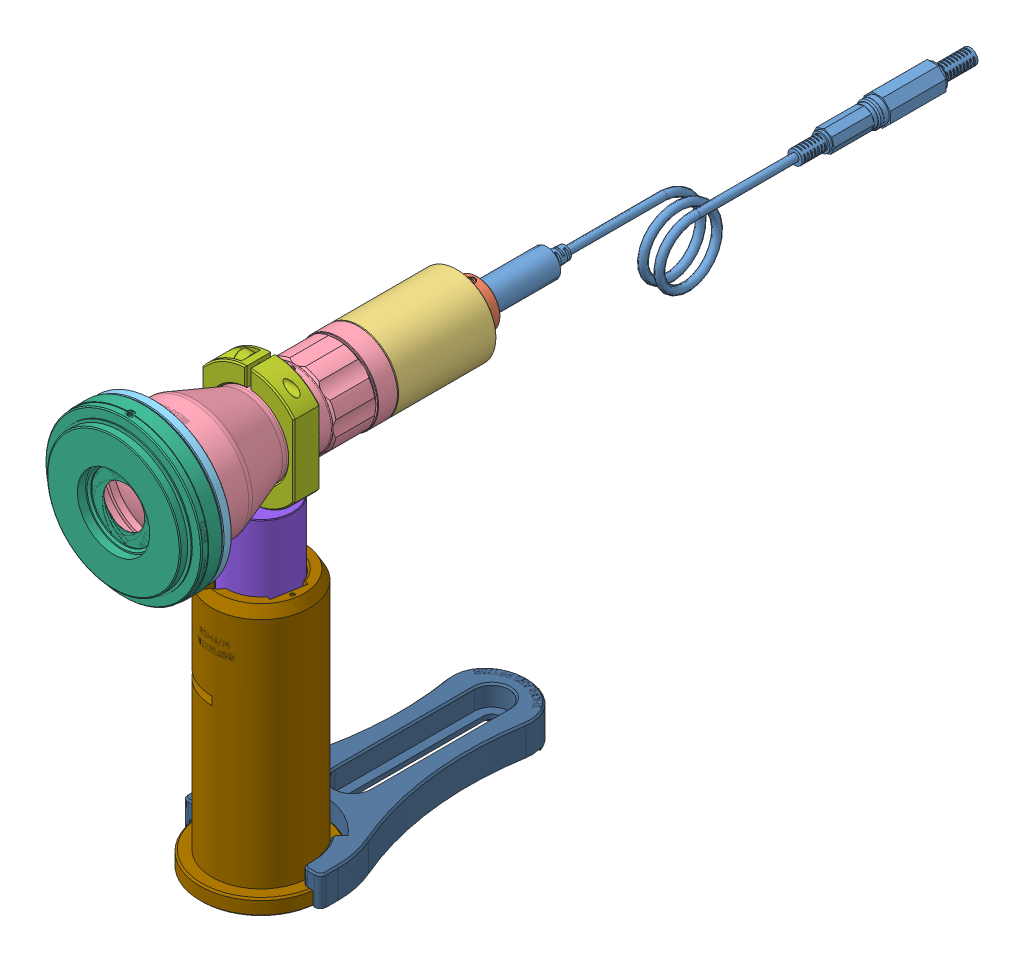
SolidWorks assembly alignment_laser_v1.0, configuration Default. Lengths in mm.
Overall size (60.96 177.6 318.27).
10 component instances, 10 part files, 28 mates.
Components (placement in the parent):
- CPS532-Solidworks-1: CPS532-Solidworks [Default] at origin size (23.32 32.38 223.65)
- AD11F-Solidworks-1: AD11F-Solidworks [Default] at (0 0 -2.981) x (-1 0 0) z (0 1 0) size (26.29 14.99 26.29)
- SM1M15-Solidworks-1: SM1M15-Solidworks [Default] at (1.3605 -23.9688 -18.2398) size (30.48 30.48 38.1)
- BE05-532-Solidworks-1: BE05-532-Solidworks [Default] at (0 0 34.5) size (45 45 85.5)
- SM2A30-Solidworks-1: SM2A30-Solidworks [Default] at (0 0 114.5) x (-1 0 0) z (0 0 -1) size (60.2 60.2 6.35)
- SM2D25D-Solidworks-1: SM2D25D-Solidworks [Default] at (6.3593 1.1475 119.8262) size (60.96 60.96 12.32)
- SM1RC_M-Solidworks-1: SM1RC_M-Solidworks [Web Drawing] at (0 0 78.26) x (-1 0 0) z (0 0 -1) size (35.56 44.69 10.16)
- RS100_M-Solidworks-1: RS100_M-Solidworks [Default] at (2.2631 -70.4202 70.8458) size (25 100 25.2)
- RSH4_M-Solidworks-1: RSH4_M-Solidworks [Default] at (36.1376 -109.0482 157.2021) x (0 0 1) z (-1 0 0) size (46.99 100.24 46.99)
- PF175B-Solidworks-1: PF175B-Solidworks [Default] at (0 -146.336 73.18) x (-1 0 0) z (0 0 -1) size (53.49 12.22 106.54)
Mates (geometry in assembly coordinates):
- Coincident1: coordinate: point of CPS532-Solidworks-1; point of assembly
- Concentric1: concentric anti-aligned: cylinder of CPS532-Solidworks-1 through (0 0 30) axis (0 0 -1) radius 5.485; cylinder of AD11F-Solidworks-1 through (0 0 -10.474) axis (0 0 1) radius 5.5372
- Coincident2: coincident aligned: plane of AD11F-Solidworks-1 through (0 0 -2.981) normal (0 1 0); plane of assembly
- Concentric2: concentric anti-aligned: cylinder of CPS532-Solidworks-1 through (0 0 30) axis (0 0 -1) radius 5.485; cylinder of SM1M15-Solidworks-1 through (0 0 35.5) axis (0 0 1) radius 13.1445
- Coincident3: coincident aligned: plane of CPS532-Solidworks-1 through (0 0 35.5) normal (0 0 1); plane of SM1M15-Solidworks-1 through (0 15.24 35.5) normal (0 0 1)
- Coincident4: coincident anti-aligned: plane of AD11F-Solidworks-1 through (0 0 -0.568) normal (0 0 -1); plane of SM1M15-Solidworks-1 through (0 0 -0.568) normal (0 0 1)
- Parallel1: parallel aligned: plane of SM1M15-Solidworks-1 through (1.3605 -23.9688 -18.2398) normal (1 0 0); plane of assembly
- Concentric3: concentric anti-aligned: cylinder of SM1M15-Solidworks-1 through (0 0 35.5) axis (0 0 1) radius 15.24; cylinder of BE05-532-Solidworks-1 through (0 0 32.5) axis (0 0 -1) radius 15.25
- Coincident6: coincident anti-aligned: plane of SM1M15-Solidworks-1 through (0 15.24 35.5) normal (0 0 1); plane of BE05-532-Solidworks-1 through (1.1774 12.8908 35.5) normal (0 0 -1)
- Coincident7: coincident aligned: plane of BE05-532-Solidworks-1 through (0 0 34.5) normal (0 1 0); plane of assembly through (0 0 0) normal (0 1 0)
- Concentric4: concentric anti-aligned: cylinder of BE05-532-Solidworks-1 through (0 0 108.1158) axis (0 0 1) radius 22.5; cylinder of SM2A30-Solidworks-1 through (0 0 114.5) axis (0 0 -1) radius 21.5
- Coincident8: coincident anti-aligned: plane of BE05-532-Solidworks-1 through (0 21.3 114.5) normal (0 0 1); plane of SM2A30-Solidworks-1 through (0 30.099 114.5) normal (0 0 -1)
- Coincident9: coincident aligned: plane of SM2A30-Solidworks-1; plane of assembly
- Concentric5: concentric aligned: cylinder of SM2A30-Solidworks-1 through (0 0 114.5) axis (0 0 -1) radius 25.8445; cylinder of SM2D25D-Solidworks-1 through (0 0 126.3872) axis (0 0 -1) radius 30.48
- Coincident10: coincident anti-aligned: plane of SM2A30-Solidworks-1 through (0 25.8445 117.802) normal (0 0 1); plane of SM2D25D-Solidworks-1 through (0 0 117.802) normal (0 0 -1)
- Parallel2: parallel aligned: plane of SM2D25D-Solidworks-1 through (6.3593 1.1475 119.8262) normal (0 1 0); plane of assembly
- Concentric7: concentric anti-aligned: cylinder of BE05-532-Solidworks-1 through (0 0 108.1158) axis (0 0 1) radius 15.25; cylinder of SM1RC_M-Solidworks-1 through (0 0 78.26) axis (0 0 -1) radius 15.3035
- Distance1: distance = 1 mm aligned: plane of SM1RC_M-Solidworks-1 through (0 0 68.1) normal (0 0 -1); plane of BE05-532-Solidworks-1 through (0 15.05 67.1) normal (0 0 -1)
- Coincident13: coincident aligned: plane of SM1RC_M-Solidworks-1; plane of assembly
- Concentric8: concentric aligned: cylinder of SM1RC_M-Solidworks-1 through (0 -22.098 73.18) axis (0 -1 0) radius 2; cylinder of RS100_M-Solidworks-1 through (0 -22.098 73.18) axis (0 -1 0) radius 12.5
- Coincident14: coincident anti-aligned: plane of SM1RC_M-Solidworks-1 through (0 -22.098 78.26) normal (0 -1 0); plane of RS100_M-Solidworks-1 through (0 -22.098 73.18) normal (0 1 0)
- Parallel3: parallel aligned: plane of RS100_M-Solidworks-1 through (2.2631 -70.4202 70.8458) normal (1 0 0); plane of assembly
- Concentric9: concentric aligned: cylinder of RS100_M-Solidworks-1 through (0 -22.098 73.18) axis (0 -1 0) radius 12.5; cylinder of RSH4_M-Solidworks-1 through (0 -47.0982 73.18) axis (0 -1 0) radius 12.7381
- Distance2: distance = 25 mm aligned: plane of RSH4_M-Solidworks-1 through (0 -147.098 31.5197) normal (0 -1 0); plane of RS100_M-Solidworks-1 through (0 -122.098 73.18) normal (0 -1 0)
- Parallel4: parallel aligned: plane of RSH4_M-Solidworks-1 through (36.1376 -109.0482 157.2021) normal (0 0 1); plane of assembly
- Concentric10: concentric anti-aligned: cylinder of RSH4_M-Solidworks-1 through (0 -47.0982 73.18) axis (0 -1 0) radius 18.8722; cylinder of PF175B-Solidworks-1 through (0 -147.098 73.18) axis (0 1 0) radius 23.876
- Coincident18: coincident aligned: plane of RSH4_M-Solidworks-1 through (0 -147.098 31.5197) normal (0 -1 0); plane of PF175B-Solidworks-1 through (-2.7521 -147.098 -15.9216) normal (0 -1 0)
- Parallel5: parallel anti-aligned: plane of PF175B-Solidworks-1 through (6.731 -142.78 -15.974) normal (-1 0 0); plane of assembly
